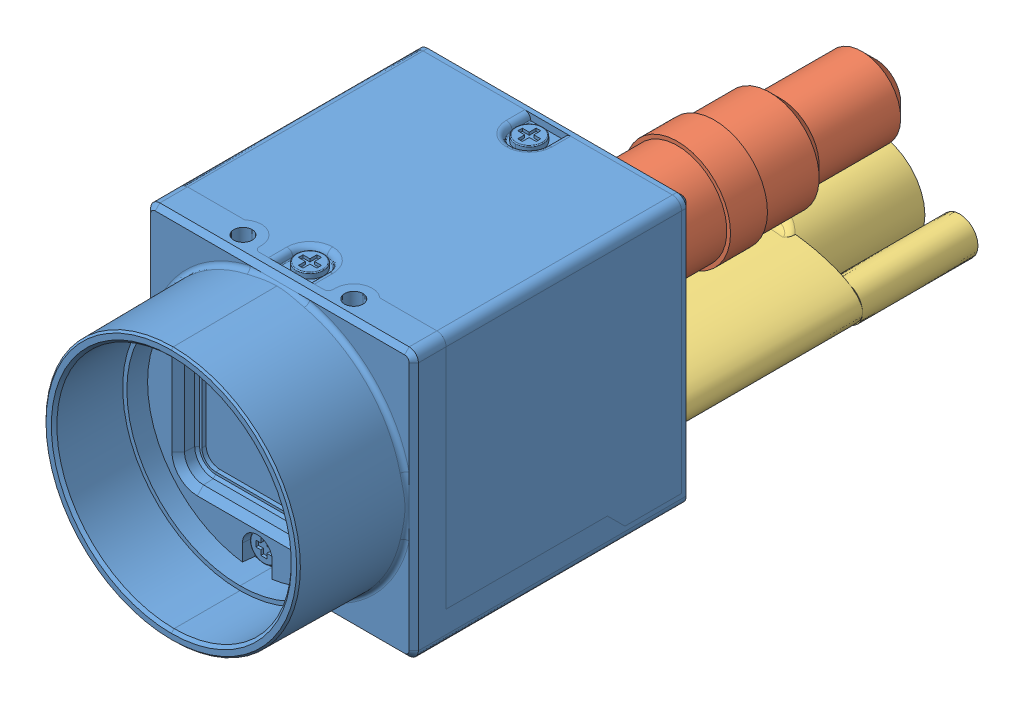
SolidWorks assembly BFS_U3, configuration Default. Lengths in mm.
Overall size (29.65 29.72 76.36).
3 component instances, 3 part files, 5 mates.
Components (placement in the parent):
- FL2-020-R0-1: FL2-020-R0 [Default] at origin size (29 29 47.76)
- round_connector-1: round_connector [Default] at (7.25 7.25 -17.9182) x (0 0 -1) z (-0.517634 -0.855602 0) size (26.5 11.5 11.5)
- wide_connector-1: wide_connector [Default] at (0 -9.325 -18.2182) x (1 0 0) z (0 0 -1) size (22 10.5 33.5)
Mates (geometry in assembly coordinates):
- Coincident1: coincident anti-aligned: plane of FL2-020-R0_V2.step-1 through (-10 -7.325 -18.2182) normal (0 0 -1); plane of wide_connector-1 through (0 -9.325 -18.2182) normal (0 0 1)
- Concentric1: concentric anti-aligned: cylinder of FL2-020-R0_V2.step-1 through (-9 -9.325 -18.2182) axis (0 0 -1) radius 1; cylinder of wide_connector-1 through (-9 -9.325 -51.7182) axis (0 0 1) radius 2
- Concentric3: concentric anti-aligned: cylinder of FL2-020-R0_V2.step-1 through (9 -9.325 -18.2182) axis (0 0 -1) radius 1; cylinder of wide_connector-1 through (9 -9.325 -51.7182) axis (0 0 1) radius 2
- Concentric5: concentric aligned: circle of FL2-020-R0_V2.step-1; circle of round_connector-1
- Coincident3: coincident anti-aligned: plane of FL2-020-R0_V2.step-1 through (7.25 7.25 -17.9182) normal (0 0 -1); plane of round_connector-1 through (11.8275 4.4807 -17.9182) normal (0 0 1)
